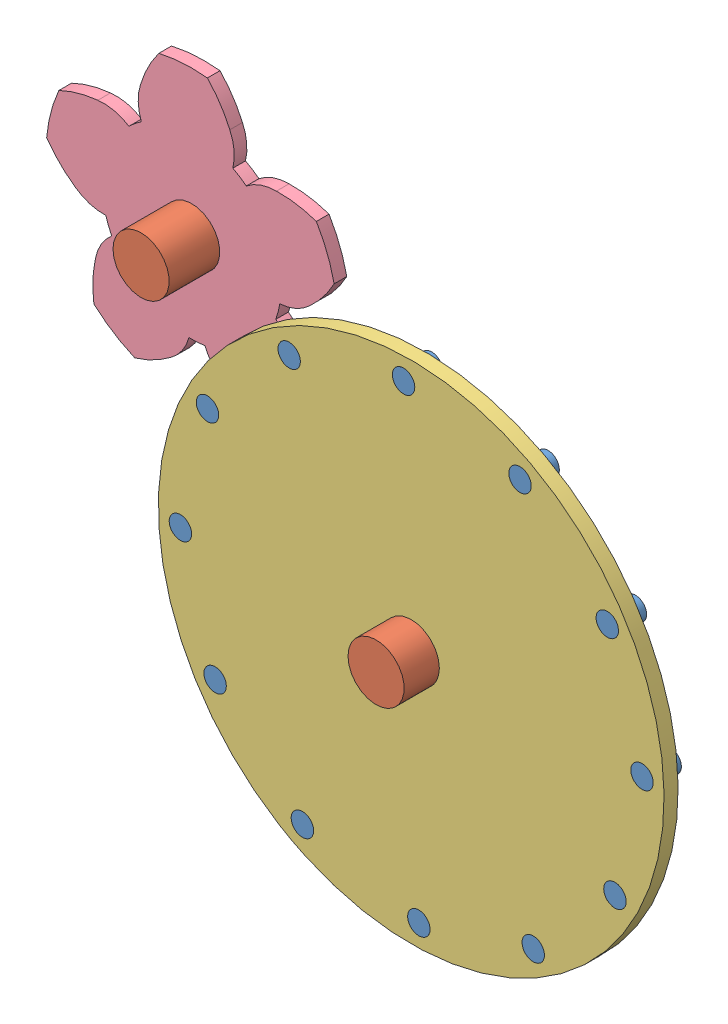
SolidWorks assembly PrzekłaZ12-5-forum, configuration Default. Lengths in mm.
Overall size (273.88 274.44 30).
5 component instances, 4 part files, 8 mates.
Components (placement in the parent):
- Tulejki-1: Tulejki [Domyślna] at (477.7436 -146.5349 0) x (-0.560696 -0.828022 0) z (0 0 1) size (171.47 171.47 10)
- wałek20-1: wałek20 [Default] at (200 -200 -7.5) size (20 20 30)
- wałek20-2: wałek20 [Default] at (116.3634 -116.3634 -7.5) size (20 20 30)
- Tarcza koła1-1: Tarcza koła1 [Domyślna] at (470.6334 -117.7957 5) x (-0.471073 -0.882094 0) z (0 0 1) size (180 180 5)
- KołoZ5Ł-Inv-1: KołoZ5Ł-Inv [Domyślna] at (-259.5119 -120.6374 0) x (0.840604 0.54165 0) z (0 0 1) size (101.81 100.54 4.5)
Mates (geometry in assembly coordinates):
- Odległość4: distance = 118.28 mm: point of wałek20-2; point of wałek20-1
- Koncentryczne7: concentric: cylinder of Tulejki-1 through (272.434 -238.8298 10) axis (0 0 -1) radius 4; cylinder of Tarcza koła1-1 through (272.434 -238.8298 10) axis (0 0 -1) radius 4
- Koncentryczne8: concentric: cylinder of Tulejki-1 through (243.3148 -269.8446 10) axis (0 0 -1) radius 4; cylinder of Tarcza koła1-1 through (243.3148 -269.8446 10) axis (0 0 -1) radius 4
- Koncentryczne9: concentric: cylinder of wałek20-1 through (200 -200 22.5) axis (0 0 -1) radius 10; cylinder of Tarcza koła1-1 through (200 -200 10) axis (0 0 -1) radius 90
- Wspólnie2: coincident: plane of Tulejki-1 through (269.8446 -156.6852 10) normal (0 0 1); plane of Tarcza koła1-1 through (200 -200 10) normal (0 0 1)
- Odległość10: distance = 12.5 mm: plane of Tarcza koła1-1 through (200 -200 10) normal (0 0 1); plane of wałek20-1 through (200 -200 22.5) normal (0 0 1)
- Koncentryczne11: concentric: cylinder of wałek20-2 through (116.3634 -116.3634 22.5) axis (0 0 -1) radius 10; cylinder of KołoZ5Ł-Inv-1 through (116.3634 -116.3634 4.5) axis (0 0 -1) radius 10
- Odległość12: distance = 0.5 mm: plane of KołoZ5Ł-Inv-1 through (162.3606 -208.0489 4.5) normal (0 0 1); plane of Tarcza koła1-1 through (200 -200 5) normal (0 0 -1)
